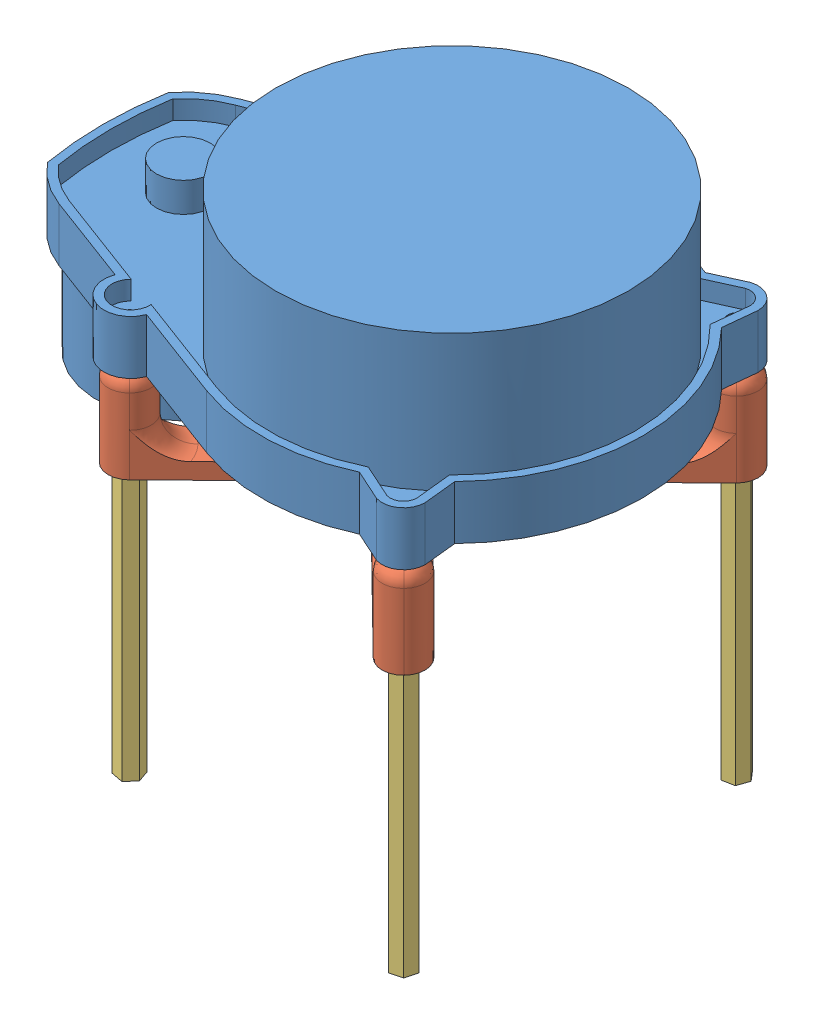
SolidWorks assembly lidar pilotis, configuration Défaut. Lengths in mm.
Overall size (101.5 99 71).
6 component instances, 3 part files, 11 mates.
Components (placement in the parent):
- ydlidar x4-1: ydlidar x4 [Défaut] at (10.6117 -7.7405 108) x (1 0 0) z (0 1 0) size (101.5 71 51)
- raccord lidar-1: raccord lidar [Défaut] at (-8.71 -21.7405 110.0037) x (-1 0 0) z (0 1 0) size (65 70 17)
- support_hex60-1: support_hex60 [Défaut] at (32.6117 -24.7405 77) x (0.94395 0 0.330089) z (0 -1 0) size (4 4.62 50)
- support_hex60-2: support_hex60 [Défaut] at (32.6117 -24.7405 139) x (0.967414 0 0.253199) z (0 -1 0) size (4 4.62 50)
- support_hex60-3: support_hex60 [Défaut] at (-24.3883 -24.7405 133) x (0.945168 0 -0.326585) z (0 -1 0) size (4 4.62 50)
- support_hex60-4: support_hex60 [Défaut] at (-24.3883 -24.7405 83) x (0.946978 0 0.321299) z (0 -1 0) size (4 4.62 50)
Mates (geometry in assembly coordinates):
- Coaxiale1: concentric anti-aligned: circle of ydlidar x4-1; circle of raccord lidar-1
- Coaxiale2: concentric aligned: circle of ydlidar x4-1; circle of raccord lidar-1
- Coïncidente1: coincident anti-aligned: plane of ydlidar x4-1 through (10.6117 -7.7405 108) normal (0 -1 0); circle of raccord lidar-1
- Coaxiale3: concentric aligned: circle of raccord lidar-1; circle of support_hex60-1
- Coïncidente2: coincident anti-aligned: plane of raccord lidar-1 through (-8.71 -24.7405 110.0037) normal (0 -1 0); plane of support_hex60-1 through (32.6117 -24.7405 77) normal (0 1 0)
- Coaxiale4: concentric aligned: circle of raccord lidar-1; circle of support_hex60-3
- Coaxiale5: concentric aligned: circle of raccord lidar-1; circle of support_hex60-4
- Coaxiale6: concentric aligned: circle of raccord lidar-1; circle of support_hex60-2
- Coïncidente3: coincident anti-aligned: plane of raccord lidar-1 through (-8.71 -24.7405 110.0037) normal (0 -1 0); plane of support_hex60-3 through (-24.3883 -24.7405 133) normal (0 1 0)
- Coïncidente4: coincident anti-aligned: plane of raccord lidar-1 through (-8.71 -24.7405 110.0037) normal (0 -1 0); plane of support_hex60-2 through (32.6117 -24.7405 139) normal (0 1 0)
- Coïncidente5: coincident anti-aligned: plane of raccord lidar-1 through (-8.71 -24.7405 110.0037) normal (0 -1 0); plane of support_hex60-4 through (-24.3883 -24.7405 83) normal (0 1 0)
